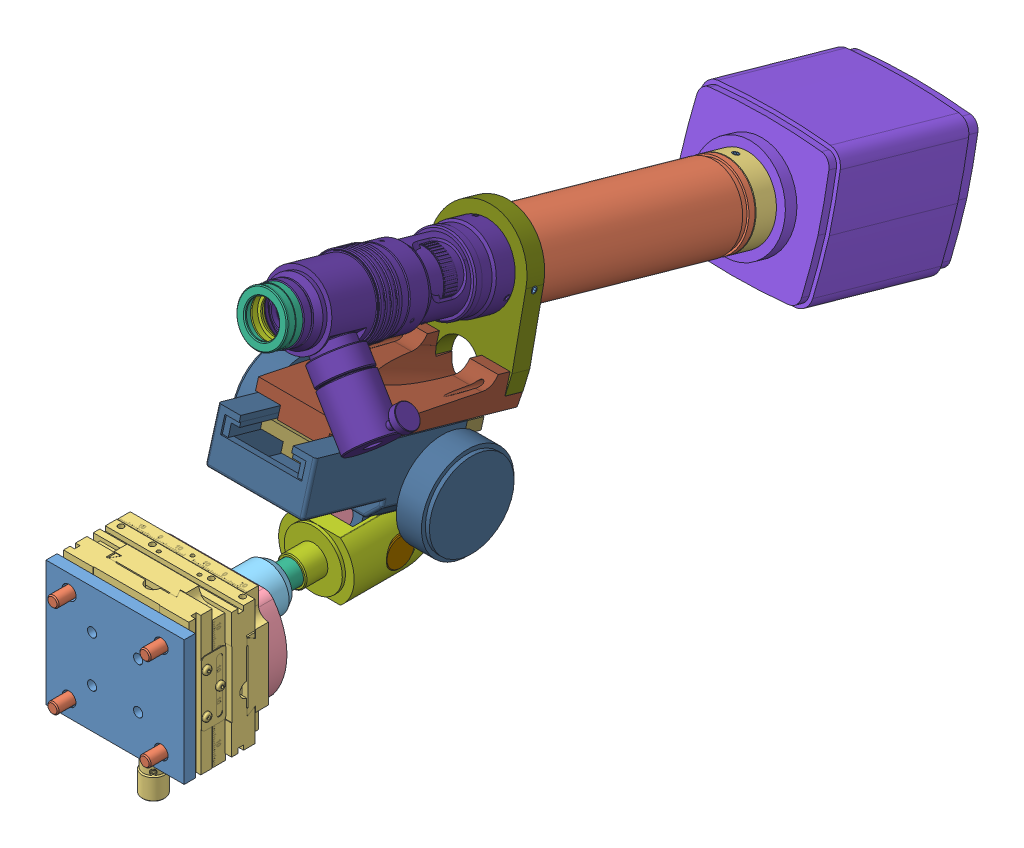
SolidWorks assembly Camera and microscope block, configuration Default. Lengths in mm.
Overall size (225.2 327.74 551.05).
43 component instances, 26 part files, 9 mates.
Components (placement in the parent):
- Camera Post-1: Camera Post [Default] at (73.6193 75.1044 120.8649) size (98.3 98.25 159.76)
  - Base altura câmara-1: Base altura câmara [Default] at (-25.0412 0.9003 65.6472) size (75 68 6)
  - socket head cap screw_iso_12-1: socket head cap screw_iso_12 [ISO 4762 M6 x 20 - 20N] at (-12.5412 9.9003 54.6472) x (0 0 1) z (-0.613808 -0.789456 0) size (26 10 10)
  - socket head cap screw_iso_12-2: socket head cap screw_iso_12 [ISO 4762 M6 x 20 - 20N] at (-12.5412 59.9003 54.6472) x (0 0 1) z (-0.468301 -0.883569 0) size (26 10 10)
  - socket head cap screw_iso_12-3: socket head cap screw_iso_12 [ISO 4762 M6 x 20 - 20N] at (37.4588 59.9003 54.6472) x (0 0 1) z (-0.701703 -0.712469 0) size (26 10 10)
  - socket head cap screw_iso_12-4: socket head cap screw_iso_12 [ISO 4762 M6 x 20 - 20N] at (37.4588 9.9003 54.6472) x (0 0 1) z (-0.710367 -0.703832 0) size (26 10 10)
  - DTS25_M-Solidworks (1)-1: DTS25_M-Solidworks (1) [Default] at (-25.0412 -24.4808 73.3972) x (-1 0 0) z (0 0 1) size (69.9 98.25 20)
  - DTS25_M-Solidworks (1)-2: DTS25_M-Solidworks (1) [Default] at (-46.9223 72.4003 53.6972) x (0 1 0) z (0 0 1) size (69.9 98.25 20)
  - BA3_M-Solidworks-1: BA3_M-Solidworks [Default] at (12.5088 34.1567 20.9472) x (-1 0 0) z (0 -1 0) size (75 10 50)
  - socket head cap screw_iso_12-5: socket head cap screw_iso_12 [ISO 4762 M6 x 16 - 16N] at (37.4588 34.9003 9.9472) x (0 0 1) z (-0.387084 -0.922044 0) size (22 10 10)
  - socket head cap screw_iso_12-6: socket head cap screw_iso_12 [ISO 4762 M6 x 16 - 16N] at (-12.5412 34.9003 9.9472) x (0 0 1) z (-0.386644 -0.922229 0) size (22 10 10)
  - socket head cap screw_iso_12-7: socket head cap screw_iso_12 [ISO 4762 M6 x 16 - 16N] at (12.5088 34.1567 25.0892) x (0 0 -1) z (-0.84234 -0.538946 0) size (22 10 10)
  - PH30_M-Solidworks-1: PH30_M-Solidworks [Default] at (13.8995 29.3922 6.5019) x (-1 0 0) z (0 -1 0) size (25 30.44 33)
  - TR50_M-Solidworks-1: TR50_M-Solidworks [Default] at (12.5088 34.1567 5.9472) x (0.965492 0.260434 0) z (-0.260434 0.965492 0) size (12.67 55.03 12.87)
  - Forquilha da camara-1: Forquilha da camara [Default] at (12.5088 34.1567 -37.5528) x (0 1 0) z (0 0 1) size (33.29 41.75 55.06)
  - slotted set screw flat point_iso_13-2: slotted set screw flat point_iso_13 [ISO 4766 - M4 x 6-N] at (12.5088 18.3067 -41.5528) x (0 1 0) z (-0.585816 0 0.810444) size (6 4 4)
  - Eixo suporte-1: Eixo suporte [Default] at (32.8088 34.1567 -62.9028) x (0 0.823026 -0.568004) z (0 0.568004 0.823026) size (15.7 40.8 15.7)
- Microscope Holder-1: Microscope Holder [Default] at (139.5071 50.1815 47.8435) x (-1 0 0) z (0 0.962636 -0.270797) size (113.5 273.92 151.76)
  - Suporte da câmara-1: Suporte da câmara [Default] at (39.179 10.2391 110.382) size (107 90.6 73.6)
  - Fixador câmara-1: Fixador câmara [Default] at (66.529 -16.9064 104.982) x (0 1 0) z (1 0 0) size (92.9 23.1 53.8)
  - Corrediça da câmara-1: Corrediça da câmara [Default] at (34.629 76.8936 104.982) x (1 0 0) z (0 0 -1) size (37.4 85.5 10.5)
  - Fixador inferior-1: Fixador inferior [Default] at (53.429 41.2391 65.132) x (0.972202 0 -0.234146) z (-0.234146 0 -0.972202) size (12.5 14 12.5)
  - Fixador superior-1: Fixador superior [Default] at (53.429 10.2391 65.132) size (12.5 14 12.5)
  - Tampa da corrediça-1: Tampa da corrediça [Default] at (26.479 9.7391 97.482) x (1 0 0) z (0 1 0) size (53.9 24.2 1.6)
  - Anel fixação lente-1: Anel fixação lente [Default] at (53.229 -8.2397 161.632) x (0 0 1) z (0 -1 0) size (70 56 10)
  - MVL6X3Z-Solidworks-1: MVL6X3Z-Solidworks [Default] at (46.5248 25.6964 134.8168) x (0 -1 0) z (-0.707107 0 -0.707107) size (134.62 45.26 83.25)
  - socket button head screw_iso-1: socket button head screw_iso [ISO 7380 - M6 x 10 - 10N] at (53.429 10.2391 65.132) x (0 1 0) z (-0.985336 0 0.170626) size (13.3 10.5 10.5)
  - socket set screw flat point_iso-3: socket set screw flat point_iso [ISO 4026 - M4 x 4-N] at (27.186 -13.2497 161.632) x (0.998348 0 -0.057463) z (0.057457 0.013867 0.998252) size (4 4 4)
  - socket set screw flat point_iso-4: socket set screw flat point_iso [ISO 4026 - M4 x 4-N] at (79.2717 -16.4497 161.6392) x (-0.998348 0 -0.057463) z (0.052772 -0.395708 -0.916859) size (4 4 4)
  - Adapter 1x-1: Adapter 1x [Default] at (53.229 -21.4147 161.632) x (-0.664073 0 -0.747667) z (-0.747667 0 0.664073) size (40.6 130.6 40.6)
  - Coupler C Mount-1: Coupler C Mount [Default] at (53.229 -143.0147 161.632) x (0.999263 0 -0.03839) z (0 1 0) size (40.6 40.6 17.5)
  - socket set screw flat point_iso-5: socket set screw flat point_iso [ISO 4026 - M4 x 4-N] at (54.0083 -149.0147 181.9171) x (-0.03839 0 -0.999263) z (0.588106 0.808468 -0.022594) size (4 4 4)
  - socket head cap screw_iso-3: socket head cap screw_iso [ISO 4762 M4 x 12 - 12N] at (75.229 -18.7397 122.632) x (0 1 0) z (0.13306 0 0.991108) size (16 7 7)
  - socket head cap screw_iso-4: socket head cap screw_iso [ISO 4762 M4 x 12 - 12N] at (31.229 -18.7397 122.632) x (0 1 0) z (0.363821 0 0.931469) size (16 7 7)
  - socket countersunk head screw_iso-1: socket countersunk head screw_iso [ISO 10642 - M3 x 8 - 8N] at (37.679 9.7391 80.682) x (0 1 0) z (0.815348 0 -0.578971) size (8 5.54 5.54)
  - socket countersunk head screw_iso-2: socket countersunk head screw_iso [ISO 10642 - M3 x 8 - 8N] at (68.979 9.7391 80.682) x (0 1 0) z (-0.65025 0 -0.75972) size (8 5.54 5.54)
  - navitar-solid-model_1-60112-1: navitar-solid-model_1-60112 [Default] at (53.229 113.4085 161.632) x (0 -1 0) z (0.701845 0 -0.71233) size (12.96 26.75 26.75)
    - navitar-solid-model_1-60112.stp-1: navitar-solid-model_1-60112.stp [Default] at origin size (12.96 26.75 26.75)
      - 60120.stp-1: 60120.stp [Default] at origin size (8.92 26.75 26.75)
      - 60121.stp-1: 60121.stp [Default] at (6.08 0 0) x (1 0 0) z (0 0.999124 0.041848) size (6.88 25 25)
- Microscope Camera-1: Microscope Camera [Default] at (46.9781 195.6235 -165.3211) x (1 0 0) z (0 0.962636 -0.270797) size (78.6 90.5 72.2)
- socket head cap screw_iso-1: socket head cap screw_iso [ISO 4762 M6 x 12 - 12N] at (111.3781 84.7047 155.8121) x (0 0 1) z (-0.997074 0.076442 0) size (18 10 10)
- socket head cap screw_iso-2: socket head cap screw_iso [ISO 4762 M6 x 12 - 12N] at (60.7781 135.3047 155.8121) x (0 0 1) z (0.844207 -0.536017 0) size (18 10 10)
Mates (geometry in assembly coordinates):
- Concentric1: concentric anti-aligned: cylinder of Camera Post-1/Eixo suporte-1 through (65.6281 109.2611 57.9621) axis (1 0 0) radius 7.85; cylinder of Microscope Holder-1/Suporte da câmara-1 through (119.3812 109.2611 57.9621) axis (-1 0 0) radius 7.85
- Coincident1: coincident anti-aligned: plane of Camera Post-1/Forquilha da camara-1 through (74.9781 164.6085 42.1121) normal (1 0 0); plane of Microscope Holder-1/Suporte da câmara-1 through (74.9781 159.212 27.8089) normal (-1 0 0)
- Concentric2: concentric anti-aligned: cylinder of Microscope Holder-1/Coupler C Mount-1 through (86.2781 167.0465 -133.5972) axis (0 0.270797 0.962636) radius 17.1608; cylinder of Microscope Camera-1 through (86.2781 163.7969 -145.1488) axis (0 -0.270797 -0.962636) radius 25
- Parallel1: parallel anti-aligned: line of Microscope Holder-1/Corrediça da câmara-1 through (67.4781 143.3272 12.7004) axis (1 0 0); line of Microscope Camera-1 through (114.7781 121.9623 -227.393) axis (-1 0 0)
- Coincident6: coincident anti-aligned: plane of Microscope Holder-1/Coupler C Mount-1 through (106.5631 164.5471 -145.3598) normal (0 -0.270797 -0.962636); plane of Microscope Camera-1 through (86.2781 163.7969 -145.1488) normal (0 0.270797 0.962636)
- Concentric3: concentric aligned: cylinder of Camera Post-1/DTS25_M-Solidworks (1)-2 through (111.3781 84.7047 154.1121) axis (0 0 -1) radius 3.75; cylinder of socket head cap screw_iso-1 through (111.3781 84.7047 124.0621) axis (0 0 -1) radius 3
- Coincident7: coincident anti-aligned: circle of Camera Post-1/DTS25_M-Solidworks (1)-2; plane of socket head cap screw_iso-1 through (111.7603 89.6901 161.8121) normal (0 0 1)
- Concentric5: concentric aligned: cylinder of Camera Post-1/DTS25_M-Solidworks (1)-2 through (60.7781 135.3047 154.1121) axis (0 0 -1) radius 5.75; cylinder of socket head cap screw_iso-2 through (60.7781 135.3047 124.0621) axis (0 0 -1) radius 5
- Coincident9: coincident anti-aligned: circle of Camera Post-1/DTS25_M-Solidworks (1)-2; plane of socket head cap screw_iso-2 through (58.098 131.0836 161.8121) normal (0 0 1)
